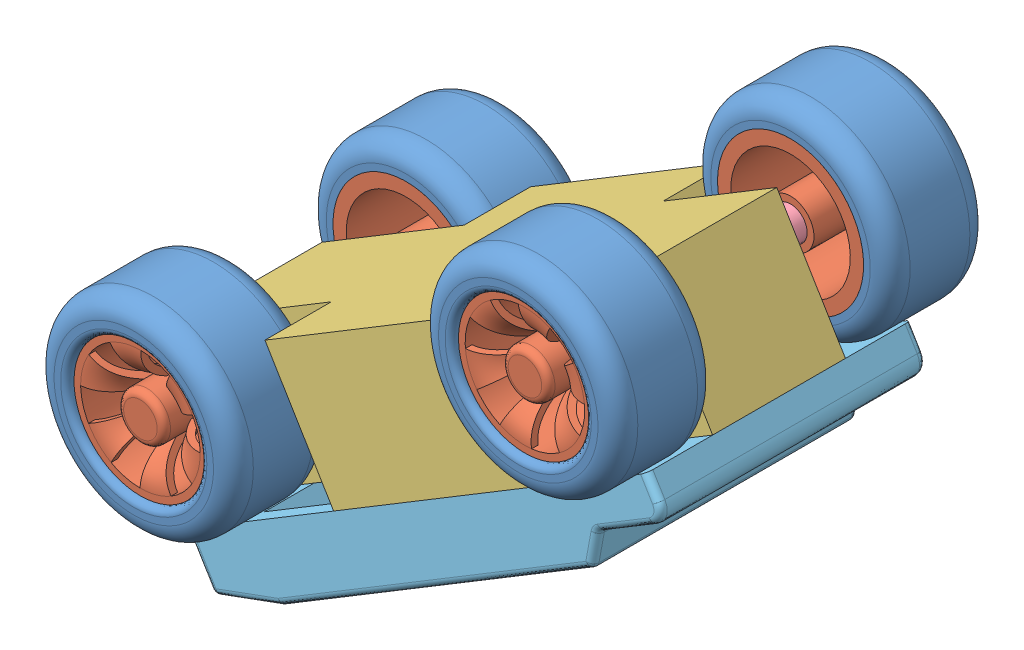
SolidWorks assembly AtulyaCompletCar, configuration Default. Lengths in mm.
Overall size (240.48 200.4 145.17).
17 component instances, 5 part files, 2 mates.
Components (placement in the parent):
- AtulyaCarBaseModel-1: AtulyaCarBaseModel [Default] at (-13.2812 75.8547 55.5743) size (240.48 181.12 145.17)
  - AtulyaCompleteWheel-1: AtulyaCompleteWheel [Default] at (-11.4674 -10.1216 -4.1326) size (76.2 76.2 38.1)
    - AtulyaTyre-1: AtulyaTyre [Default] at (7.3358 39.6521 69.7052) size (76.2 76.2 38.1)
    - AtulyaWheelRim-1: AtulyaWheelRim [Default] at (-8.0982 67.2966 79.857) x (0 0 -1) z (1 0 0) size (36.6 55.88 55.88)
  - AtulyaCarBase-1: AtulyaCarBase [Default] at (74.5767 24.2516 151.014) x (0.855878 0.517178 0) z (-0.517178 0.855878 0) size (203.2 101.6 50.8)
  - AtulyaAxle-1: AtulyaAxle [Default] at (-50.7421 6.7659 200.1925) x (-0.854807 -0.518947 0) z (0 0 -1) size (12.7 12.7 127)
  - AtulyaAxle-2: AtulyaAxle [Default] at (168.0831 153.0501 203.1257) x (0.951085 0.30893 0) z (0 0 -1) size (12.7 12.7 127)
  - AtulyaCompleteWheel-2: AtulyaCompleteWheel [Default] at (-68.7826 34.5823 277.5177) x (-0.243513 0.969898 0) z (0 0 -1) size (76.2 76.2 38.1)
    - AtulyaTyre-1: AtulyaTyre [Default] at (7.3358 39.6521 69.7052) size (76.2 76.2 38.1)
    - AtulyaWheelRim-1: AtulyaWheelRim [Default] at (-8.0982 67.2966 79.857) x (0 0 -1) z (1 0 0) size (36.6 55.88 55.88)
  - AtulyaCompleteWheel-3: AtulyaCompleteWheel [Default] at (147.0118 82.7159 -1.1995) x (0.984272 0.176662 0) z (0 0 1) size (76.2 76.2 38.1)
    - AtulyaTyre-1: AtulyaTyre [Default] at (7.3358 39.6521 69.7052) size (76.2 76.2 38.1)
    - AtulyaWheelRim-1: AtulyaWheelRim [Default] at (-8.0982 67.2966 79.857) x (0 0 -1) z (1 0 0) size (36.6 55.88 55.88)
  - AtulyaCompleteWheel-4: AtulyaCompleteWheel [Default] at (83.9311 145.8347 280.4508) x (0.177258 0.984164 0) z (0 0 -1) size (76.2 76.2 38.1)
    - AtulyaTyre-1: AtulyaTyre [Default] at (7.3358 39.6521 69.7052) size (76.2 76.2 38.1)
    - AtulyaWheelRim-1: AtulyaWheelRim [Default] at (-8.0982 67.2966 79.857) x (0 0 -1) z (1 0 0) size (36.6 55.88 55.88)
- AtulyaShell-1: AtulyaShell [Default] at (97.0505 143.0467 143.1036) x (-0.855878 -0.517178 0) z (0 0 1) size (205.74 25.4 101.6)
Mates (geometry in assembly coordinates):
- Coincident1: coincident anti-aligned: line of AtulyaCarBaseModel-1/AtulyaCarBase-1 through (144.4675 177.0737 168.5036) axis (0 0 1); line of AtulyaShell-1 through (144.4675 177.0737 242.1636) axis (0 0 -1)
- Coincident2: coincident anti-aligned: line of AtulyaCarBaseModel-1/AtulyaCarBase-1 through (24.9014 104.8239 244.7036) axis (0.855878 0.517178 0); line of AtulyaShell-1 through (142.2936 175.7601 244.7036) axis (-0.855878 -0.517178 0)
